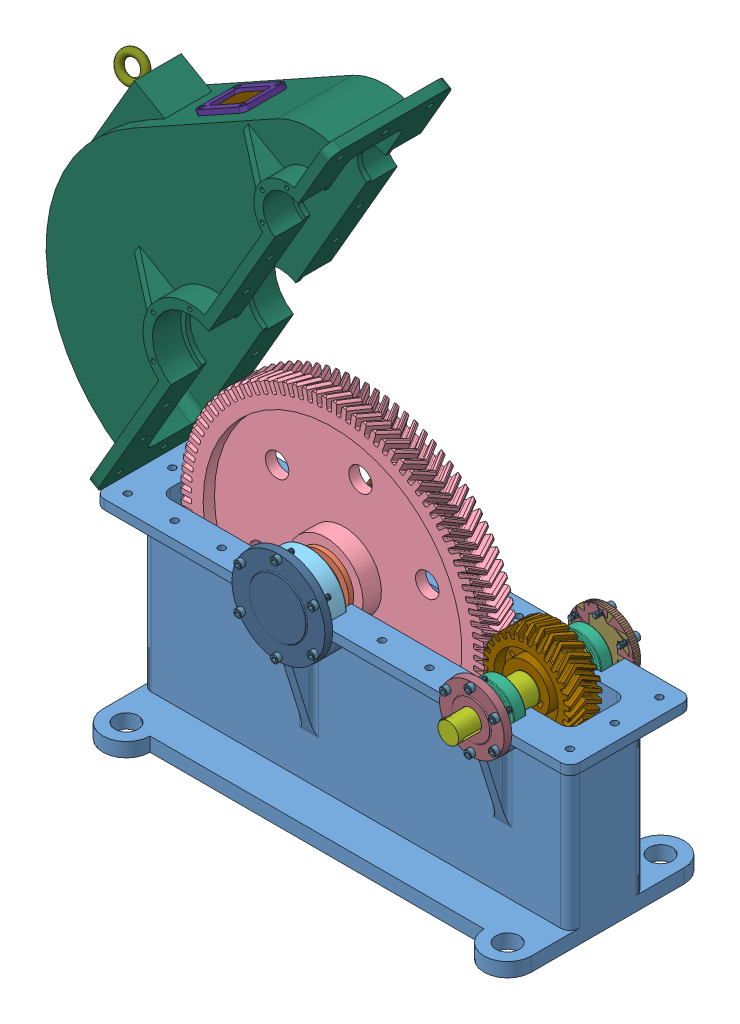
SolidWorks assembly Assem2, configuration Default. Lengths in mm.
Overall size (1319.5 1438.37 425).
47 component instances, 18 part files, 39 mates.
Components (placement in the parent):
- lower casing-1: lower casing [Default] at (-79.3234 131.3055 83.4325) size (1010 385 425)
- Gear shaft assem-1: Gear shaft assem [Default] at (-176.5675 135.1105 41.8519) x (0 0 -1) z (0.188199 0.982131 0) size (315 651.09 651.14)
  - Gear Shaft-1: Gear Shaft [Default] at (-151.5806 1.5388 -4.169) size (315 120 120)
  - gear key-1: gear key [Default] at (-72.5806 1.5388 -49.169) x (0 -1 0) z (1 0 0) size (22 22 70)
  - gear-1: gear [Default] at (-36.5806 1.5388 -4.169) x (-1 0 0) z (0 -1 0) size (100 651.14 651.09)
- single row radial ball bearing_is-3: single row radial ball bearing_is [IS 6455 SR - 03-75-S] at (-178.8634 131.3055 181.9325) size (160 160 37)
- single row radial ball bearing_is-4: single row radial ball bearing_is [IS 6455 SR - 03-75-S] at (-178.8634 131.3055 -15.0675) x (-0.396037 -0.918235 0) z (0 0 1) size (160 160 37)
- self aligning roller bearing_is-1: self aligning roller bearing_is [IS 6454 SA - 03-45-S] at (232.0966 131.3055 175.9325) size (100 100 25)
- self aligning roller bearing_is-2: self aligning roller bearing_is [IS 6454 SA - 03-45-S] at (232.0966 131.3055 -9.0675) size (100 100 25)
- pinion shaft assem-1: pinion shaft assem [Default] at (225.6575 123.2605 138.4719) x (0 0 -1) z (-0.907171 0.420761 0) size (315 187.16 187.15)
  - Pinion shaft-1: Pinion shaft [Default] at (-139.9606 -10.0075 -2.4563) size (315 90 90)
  - pinion key-1: pinion key [Default] at (38.5601 -10.0075 -32.4563) x (0 0 -1) z (1 0 0) size (15 15 45)
  - Pinion2-1: Pinion2 [Default] at (60.0394 -10.0075 -2.4563) x (-1 0 0) z (0 -1 0) size (70.01 187.15 187.16)
- G_bearingCover_c-1: G_bearingCover_c [Default] at (-178.8634 131.3055 213.4325) size (200 200 17)
- G_bearingCover_o-1: G_bearingCover_o [Default] at (-178.8634 131.3055 -46.5675) x (-0.5 -0.866025 0) z (0 0 -1) size (200 200 17)
- P_bearingCover_c-1: P_bearingCover_c [Default] at (232.0966 131.3055 -46.5675) x (-1 0 0) z (0 0 -1) size (140 140 17)
- P_bearingCover_o-1: P_bearingCover_o [Default] at (232.0966 131.3055 213.4325) size (140 140 17)
- socket head cap screw_am-25: socket head cap screw_am [B18.3.1M - 10 x 1.5 x 30 Hex SHCS -- 30SHX] at (-178.8634 41.3055 238.4325) x (0 0 -1) z (1 0 0) size (40 16 16)
- socket head cap screw_am-26: socket head cap screw_am [B18.3.1M - 10 x 1.5 x 30 Hex SHCS -- 30SHX] at (-100.9212 86.3055 238.4325) x (0 0 -1) z (0.5 0.866025 0) size (40 16 16)
- socket head cap screw_am-27: socket head cap screw_am [B18.3.1M - 10 x 1.5 x 30 Hex SHCS -- 30SHX] at (-100.9212 176.3055 238.4325) x (0 0 -1) z (-0.5 0.866025 0) size (40 16 16)
- socket head cap screw_am-28: socket head cap screw_am [B18.3.1M - 10 x 1.5 x 30 Hex SHCS -- 30SHX] at (-178.8634 221.3055 238.4325) x (0 0 -1) z (-1 0 0) size (40 16 16)
- socket head cap screw_am-29: socket head cap screw_am [B18.3.1M - 10 x 1.5 x 30 Hex SHCS -- 30SHX] at (-256.8057 176.3055 238.4325) x (0 0 -1) z (-0.5 -0.866025 0) size (40 16 16)
- socket head cap screw_am-30: socket head cap screw_am [B18.3.1M - 10 x 1.5 x 30 Hex SHCS -- 30SHX] at (-256.8057 86.3055 238.4325) x (0 0 -1) z (0.5 -0.866025 0) size (40 16 16)
- socket head cap screw_am-31: socket head cap screw_am [B18.3.1M - 10 x 1.5 x 30 Hex SHCS -- 30SHX] at (-178.8634 41.3055 -71.5675) x (0 0 1) z (-1 0 0) size (40 16 16)
- socket head cap screw_am-32: socket head cap screw_am [B18.3.1M - 10 x 1.5 x 30 Hex SHCS -- 30SHX] at (-100.9212 86.3055 -71.5675) x (0 0 1) z (-0.5 -0.866025 0) size (40 16 16)
- socket head cap screw_am-33: socket head cap screw_am [B18.3.1M - 10 x 1.5 x 30 Hex SHCS -- 30SHX] at (-100.9212 176.3055 -71.5675) x (0 0 1) z (0.5 -0.866025 0) size (40 16 16)
- socket head cap screw_am-34: socket head cap screw_am [B18.3.1M - 10 x 1.5 x 30 Hex SHCS -- 30SHX] at (-178.8634 221.3055 -71.5675) x (0 0 1) z (1 0 0) size (40 16 16)
- socket head cap screw_am-35: socket head cap screw_am [B18.3.1M - 10 x 1.5 x 30 Hex SHCS -- 30SHX] at (-256.8057 176.3055 -71.5675) x (0 0 1) z (0.5 0.866025 0) size (40 16 16)
- socket head cap screw_am-36: socket head cap screw_am [B18.3.1M - 10 x 1.5 x 30 Hex SHCS -- 30SHX] at (-256.8057 86.3055 -71.5675) x (0 0 1) z (-0.5 0.866025 0) size (40 16 16)
- socket head cap screw_am-43: socket head cap screw_am [B18.3.1M - 10 x 1.5 x 30 Hex SHCS -- 30SHX] at (232.0966 71.3055 238.4325) x (0 0 -1) z (1 0 0) size (40 16 16)
- socket head cap screw_am-44: socket head cap screw_am [B18.3.1M - 10 x 1.5 x 30 Hex SHCS -- 30SHX] at (284.0581 101.3055 238.4325) x (0 0 -1) z (0.5 0.866025 0) size (40 16 16)
- socket head cap screw_am-45: socket head cap screw_am [B18.3.1M - 10 x 1.5 x 30 Hex SHCS -- 30SHX] at (284.0581 161.3055 238.4325) x (0 0 -1) z (-0.5 0.866025 0) size (40 16 16)
- socket head cap screw_am-46: socket head cap screw_am [B18.3.1M - 10 x 1.5 x 30 Hex SHCS -- 30SHX] at (232.0966 191.3055 238.4325) x (0 0 -1) z (-1 0 0) size (40 16 16)
- socket head cap screw_am-47: socket head cap screw_am [B18.3.1M - 10 x 1.5 x 30 Hex SHCS -- 30SHX] at (180.135 161.3055 238.4325) x (0 0 -1) z (-0.5 -0.866025 0) size (40 16 16)
- socket head cap screw_am-48: socket head cap screw_am [B18.3.1M - 10 x 1.5 x 30 Hex SHCS -- 30SHX] at (180.135 101.3055 238.4325) x (0 0 -1) z (0.5 -0.866025 0) size (40 16 16)
- socket head cap screw_am-49: socket head cap screw_am [B18.3.1M - 10 x 1.5 x 30 Hex SHCS -- 30SHX] at (232.0966 191.3055 -71.5675) x (0 0 1) z (1 0 0) size (40 16 16)
- P_bearingCover_o-2: P_bearingCover_o [Default] at (232.0966 131.3055 -46.5675) x (1 0 0) z (0 0 -1) size (140 140 17)
- socket head cap screw_am-50: socket head cap screw_am [B18.3.1M - 10 x 1.5 x 30 Hex SHCS -- 30SHX] at (180.135 101.3055 -71.5675) x (0 0 1) z (-0.5 0.866025 0) size (40 16 16)
- socket head cap screw_am-51: socket head cap screw_am [B18.3.1M - 10 x 1.5 x 30 Hex SHCS -- 30SHX] at (284.0581 101.3055 -71.5675) x (0 0 1) z (-0.5 -0.866025 0) size (40 16 16)
- socket head cap screw_am-52: socket head cap screw_am [B18.3.1M - 10 x 1.5 x 30 Hex SHCS -- 30SHX] at (284.0581 161.3055 -71.5675) x (0 0 1) z (0.5 -0.866025 0) size (40 16 16)
- socket head cap screw_am-53: socket head cap screw_am [B18.3.1M - 10 x 1.5 x 30 Hex SHCS -- 30SHX] at (232.0966 71.3055 -71.5675) x (0 0 1) z (-1 0 0) size (40 16 16)
- socket head cap screw_am-54: socket head cap screw_am [B18.3.1M - 10 x 1.5 x 30 Hex SHCS -- 30SHX] at (180.135 161.3055 -71.5675) x (0 0 1) z (0.5 0.866025 0) size (40 16 16)
- Upper_housing-1: Upper_housing [Default] at (-331.8234 568.6483 83.4325) x (0.5 0.866025 0) z (0 0 1) size (1010 357.38 260)
- eyebolt-type2_ai-6: eyebolt-type2_ai [AI 18.15_type2 0.62x4.56-N-1.38] at (-634.0807 826.1927 83.4325) x (0.866025 -0.5 0) z (0.479842 0.831112 -0.281078) size (115.82 25.4 65.02)
- glasswindow_cover-1: glasswindow_cover [Default] at (-406.4142 880.7798 81.6498) x (0.873787 0.486308 0) z (0 0 -1) size (120 10 95)
  - glasscover-1: glasscover [Default] at (4.3361 -5.8911 -1.6827) size (120 10 95)
  - Glasswindow-1: Glasswindow [Default] at (4.3361 1.1089 -1.6827) size (95 3 70)
Mates (geometry in assembly coordinates):
- Concentric4: concentric anti-aligned: cylinder of lower casing-1 through (-178.8634 131.3055 245.9335) axis (0 0 -1) radius 80; cylinder of single row radial ball bearing_is-3 through (-178.8634 131.3055 232.3241) axis (0 0 1) radius 80
- Concentric5: concentric aligned: cylinder of lower casing-1 through (-178.8634 131.3055 -79.0685) axis (0 0 1) radius 80; cylinder of single row radial ball bearing_is-4 through (-178.8634 131.3055 35.3241) axis (0 0 1) radius 80
- Coincident4: coincident anti-aligned: plane of lower casing-1 through (-178.8634 131.3055 163.4325) normal (0 0 1); plane of single row radial ball bearing_is-3 through (-178.8634 211.3055 163.4325) normal (0 0 -1)
- Coincident5: coincident anti-aligned: plane of lower casing-1 through (-178.8634 131.3055 3.4325) normal (0 0 -1); plane of single row radial ball bearing_is-4 through (-105.4047 99.6226 3.4325) normal (0 0 1)
- Concentric6: concentric anti-aligned: cylinder of Gear shaft assem-1/Gear Shaft-1 through (-178.8634 131.3055 -121.5675) axis (0 0 -1) radius 37.5; cylinder of single row radial ball bearing_is-4 through (-178.8634 131.3055 55.7951) axis (0 0 1) radius 37.5
- Coincident6: coincident anti-aligned: plane of Gear shaft assem-1/Gear Shaft-1 through (-187.3324 87.1096 3.4325) normal (0 0 -1); plane of single row radial ball bearing_is-4 through (-144.4296 116.4541 3.4325) normal (0 0 1)
- Concentric7: concentric anti-aligned: cylinder of lower casing-1 through (232.0966 131.3055 245.9335) axis (0 0 -1) radius 50; cylinder of self aligning roller bearing_is-1 through (232.0966 131.3055 226.3241) axis (0 0 1) radius 50
- Concentric8: concentric aligned: cylinder of lower casing-1 through (232.0966 131.3055 -79.0685) axis (0 0 1) radius 50; cylinder of self aligning roller bearing_is-2 through (232.0966 131.3055 41.3241) axis (0 0 1) radius 50
- Coincident7: coincident anti-aligned: plane of lower casing-1 through (232.0966 131.3055 163.4325) normal (0 0 1); plane of self aligning roller bearing_is-1 through (232.0966 181.3055 163.4325) normal (0 0 -1)
- Coincident8: coincident anti-aligned: plane of lower casing-1 through (232.0966 131.3055 3.4325) normal (0 0 -1); plane of self aligning roller bearing_is-2 through (232.0966 181.3055 3.4325) normal (0 0 1)
- Concentric9: concentric aligned: cylinder of self aligning roller bearing_is-2 through (232.0966 131.3055 61.7951) axis (0 0 1) radius 22.5; cylinder of pinion shaft assem-1/Pinion shaft-1 through (232.0966 131.3055 401.7857) axis (0 0 1) radius 30
- Concentric10: concentric aligned: cylinder of self aligning roller bearing_is-1 through (232.0966 131.3055 246.7951) axis (0 0 1) radius 22.5; cylinder of pinion shaft assem-1/Pinion shaft-1 through (232.0966 131.3055 401.7857) axis (0 0 1) radius 30
- Coincident10: coincident anti-aligned: plane of self aligning roller bearing_is-2 through (232.0966 153.8055 3.4325) normal (0 0 1); plane of pinion shaft assem-1/Pinion shaft-1 through (259.3117 118.6827 3.4325) normal (0 0 -1)
- GearMate3: gear = 650.92 : 187.01 mm: cylinder of pinion shaft assem-1/Pinion2-1 through (232.0966 131.3055 43.4325) axis (0 0 -1) radius 93.505; cylinder of Gear shaft assem-1/gear-1 through (-178.8634 131.3055 78.4325) axis (0 0 -1) radius 325.46
- Coincident12: coincident anti-aligned: plane of lower casing-1 through (425.6766 111.3055 213.4325) normal (0 0 1); plane of G_bearingCover_c-1 through (-178.8634 131.3055 213.4325) normal (0 0 -1)
- Concentric11: concentric aligned: cylinder of lower casing-1 through (-178.8634 41.3055 213.4325) axis (0 0 1) radius 4.4; cylinder of G_bearingCover_c-1 through (-178.8634 41.3055 228.4325) axis (0 0 1) radius 4.4
- Concentric12: concentric aligned: cylinder of lower casing-1 through (-100.9212 86.3055 213.4325) axis (0 0 1) radius 4.4; cylinder of G_bearingCover_c-1 through (-100.9212 86.3055 228.4325) axis (0 0 1) radius 4.4
- Coincident13: coincident anti-aligned: plane of lower casing-1 through (425.6766 111.3055 -46.5675) normal (0 0 -1); plane of G_bearingCover_o-1 through (-178.8634 131.3055 -46.5675) normal (0 0 1)
- Concentric13: concentric aligned: cylinder of lower casing-1 through (-178.8634 41.3055 -46.5675) axis (0 0 -1) radius 4.4; cylinder of G_bearingCover_o-1 through (-178.8634 41.3055 -61.5675) axis (0 0 -1) radius 4.4
- Concentric14: concentric aligned: cylinder of lower casing-1 through (-256.8057 86.3055 -46.5675) axis (0 0 -1) radius 4.4; cylinder of G_bearingCover_o-1 through (-256.8057 86.3055 -61.5675) axis (0 0 -1) radius 4.4
- Coincident14: coincident anti-aligned: plane of lower casing-1 through (425.6766 111.3055 -46.5675) normal (0 0 -1); plane of P_bearingCover_c-1 through (232.0966 131.3055 -46.5675) normal (0 0 1)
- Concentric15: concentric aligned: cylinder of lower casing-1 through (232.0966 71.3055 -46.5675) axis (0 0 -1) radius 4.4; cylinder of P_bearingCover_c-1 through (232.0966 71.3055 -61.5675) axis (0 0 -1) radius 4.4
- Concentric16: concentric aligned: cylinder of lower casing-1 through (284.0581 101.3055 -46.5675) axis (0 0 -1) radius 4.4; cylinder of P_bearingCover_c-1 through (284.0581 101.3055 -61.5675) axis (0 0 -1) radius 4.4
- Coincident15: coincident anti-aligned: plane of lower casing-1 through (425.6766 111.3055 213.4325) normal (0 0 1); plane of P_bearingCover_o-1 through (232.0966 131.3055 213.4325) normal (0 0 -1)
- Concentric17: concentric aligned: cylinder of lower casing-1 through (232.0966 71.3055 213.4325) axis (0 0 1) radius 4.4; cylinder of P_bearingCover_o-1 through (232.0966 71.3055 228.4325) axis (0 0 1) radius 4.4
- Concentric18: concentric aligned: cylinder of lower casing-1 through (284.0581 101.3055 213.4325) axis (0 0 1) radius 4.4; cylinder of P_bearingCover_o-1 through (284.0581 101.3055 228.4325) axis (0 0 1) radius 4.4
- Concentric231: concentric aligned: cylinder of G_bearingCover_c-1 through (-178.8634 41.3055 228.4325) axis (0 0 1) radius 4.4; cylinder of socket head cap screw_am-25 through (-178.8634 41.3055 270.1825) axis (0 0 1) radius 8
- Coincident201: coincident anti-aligned: plane of G_bearingCover_c-1 through (-178.8634 131.3055 228.4325) normal (0 0 1); plane of socket head cap screw_am-25 through (-178.8634 49.3055 228.4325) normal (0 0 -1)
- Concentric251: concentric aligned: cylinder of P_bearingCover_o-1 through (232.0966 71.3055 228.4325) axis (0 0 1) radius 4.4; cylinder of socket head cap screw_am-43 through (232.0966 71.3055 270.1825) axis (0 0 1) radius 8
- Coincident221: coincident anti-aligned: plane of P_bearingCover_o-1 through (232.0966 131.3055 228.4325) normal (0 0 1); plane of socket head cap screw_am-43 through (232.0966 79.3055 228.4325) normal (0 0 -1)
- Coincident226: coincident aligned: line of lower casing-1 through (-584.3234 131.3055 -26.5675) axis (0 0 1); line of Upper_housing-1 through (-584.3234 131.3055 -26.5675) axis (0 0 1)
- Angle1: planar angle = 2.094395 rad aligned: plane of Upper_housing-1 through (-79.3234 1005.9912 213.4325) normal (0.866025 -0.5 0); plane of lower casing-1 through (-584.3234 131.3055 -46.5675) normal (0 1 0)
- Coincident229: coincident aligned: line of lower casing-1 through (-584.3234 131.3055 -26.5675) axis (0 0 1); line of Upper_housing-1 through (-584.3234 131.3055 -26.5675) axis (0 0 1)
- Coincident230: coincident: moEndPointRef_w of lower casing-1; moEndPointRef_w of Upper_housing-1
- Concentric256: concentric anti-aligned: cylinder of Upper_housing-1 through (-605.3639 809.6131 83.4325) axis (-0.866025 0.5 0) radius 7.3419; cylinder of eyebolt-type2_ai-6 through (-561.9304 784.5367 83.4325) axis (0.866025 -0.5 0) radius 7.874
- Coincident235: coincident anti-aligned: plane of Upper_housing-1 through (-680.3639 679.7093 33.4325) normal (-0.866025 0.5 0); plane of eyebolt-type2_ai-6 through (-611.4579 799.058 87.0022) normal (0.866025 -0.5 0)
- Coincident243: coincident anti-aligned: line of Upper_housing-1 through (-433.3941 861.0616 118.3325) axis (0.873787 0.486308 0); line of glasswindow_cover-1/glasscover-1 through (-367.8601 897.5347 118.3325) axis (-0.873787 -0.486308 0)
- Coincident245: coincident anti-aligned: plane of Upper_housing-1 through (-246.6117 965.0157 3.4325) normal (-0.486308 0.873787 0); plane of glasswindow_cover-1/glasscover-1 through (-453.0544 850.1196 130.8325) normal (0.486308 -0.873787 0)
- Coincident246: coincident anti-aligned: line of Upper_housing-1 through (-442.132 856.1985 58.3325) axis (0 0 1); line of glasswindow_cover-1/Glasswindow-1 through (-442.132 856.1985 108.3325) axis (0 0 -1)
